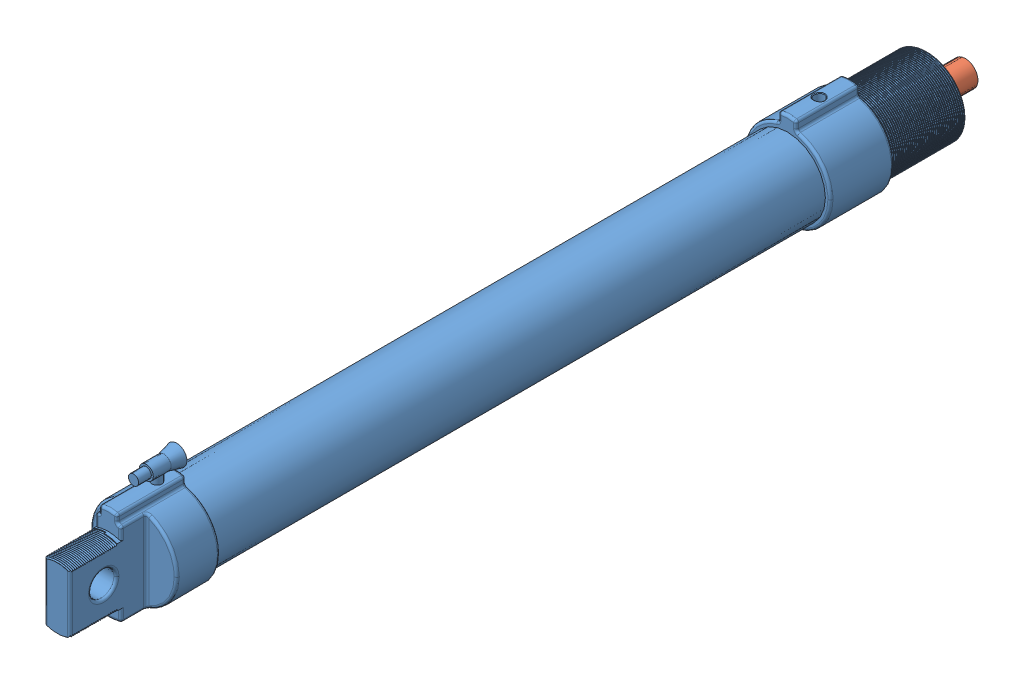
SolidWorks assembly piston-rod, configuration Default. Lengths in mm.
Overall size (40.07 46.79 357.68).
2 component instances, 2 part files, 2 mates.
Components (placement in the parent):
- cylender-1: cylender [Default] at (36.6911 203.0781 180.4291) size (40.07 46.79 343.61)
- rod-1: rod [Default] at (36.6911 203.0781 370.4291) x (0.971127 0.238561 0) z (0 0 -1) size (26 26 290)
Mates (geometry in assembly coordinates):
- Concentric1: concentric aligned: cylinder of cylender-1 through (36.6911 203.0781 180.4291) axis (0 0 1) radius 15; cylinder of rod-1 through (36.6911 203.0781 130.4291) axis (0 0 1) radius 5
- LimitDistance1: limit distance = 20 mm anti-aligned: plane of rod-1 through (36.6911 203.0781 400.4291) normal (0 0 1); plane of cylender-1 through (20.4991 186.8672 420.4291) normal (0 0 -1)
